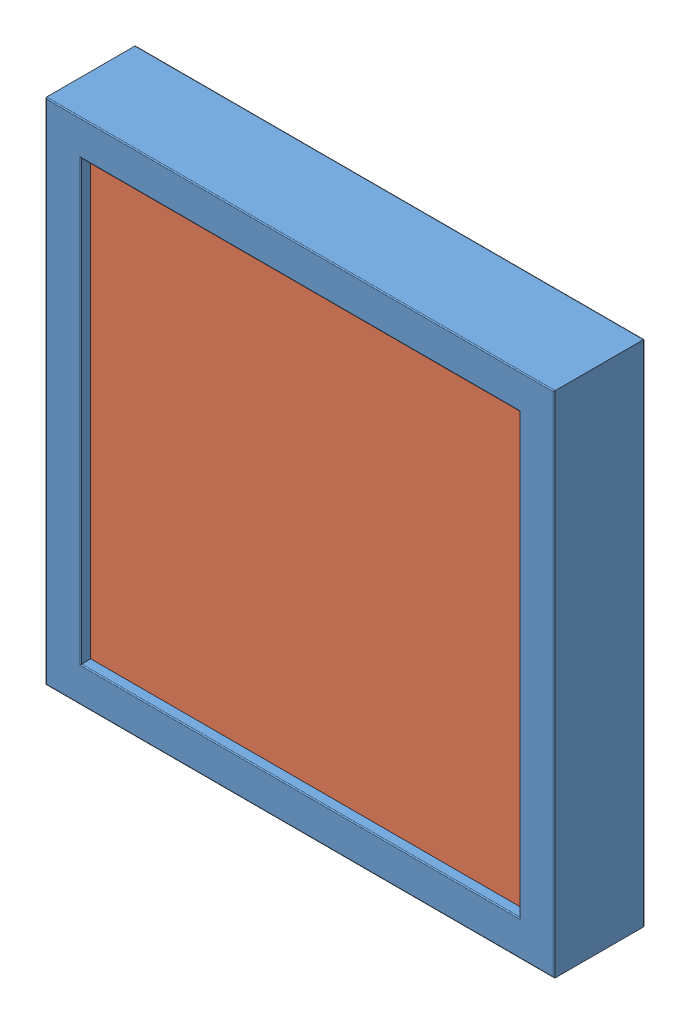
SolidWorks assembly RIBBA, configuration Default. Lengths in mm.
Overall size (254 254 45).
5 component instances, 5 part files, 16 mates.
Components (placement in the parent):
- Outer^RIBBA-1: Outer^RIBBA [Default] at origin size (254 254 45) (virtual)
- Glass^RIBBA-1: Glass^RIBBA [Default] at (0 0 -5) x (-1 0 0) z (0 0 -1) size (232 232 2) (virtual)
- Inner^RIBBA-1: Inner^RIBBA [Default] at (0 0 -7) x (-1 0 0) z (0 0 -1) size (230 230 30) (virtual)
- Matte^RIBBA-1: Matte^RIBBA [Default] at (0 0 -37) x (-1 0 0) z (0 0 -1) size (230 230 1.1) (hidden, virtual)
- Back^RIBBA-1: Back^RIBBA [Default] at (0 0 -38.1) x (-1 0 0) z (0 0 -1) size (230 230 2.65) (virtual)
Mates (geometry in assembly coordinates):
- InPlace1: in place: plane of Outer^RIBBA-1 through (0 0 -5) normal (0 0 -1); plane of Glass^RIBBA-1 through (0 0 -5) normal (0 0 -1); moOrthogonalPlaneRef_w of Outer^RIBBA-1 through (0 0 -5) normal (0 0 -1); unknown of Glass^RIBBA-1; plane of Outer^RIBBA-1 through (0 0 -5) normal (0 0 -1); plane of Glass^RIBBA-1 through (0 0 -5) normal (-1 0 0); plane of Outer^RIBBA-1 through (0 0 -5) normal (0 0 -1); unknown of Glass^RIBBA-1
- Coincident1: coincident aligned: plane of Outer^RIBBA-1; plane of Glass^RIBBA-1
- Coincident2: coincident aligned: moOrthogonalPlaneRef_w of Outer^RIBBA-1 through (0 0 -5) normal (0 1 0); plane of Glass^RIBBA-1 through (0 0 -5) normal (0 1 0)
- Coincident3: coincident anti-aligned: moOrthogonalPlaneRef_w of Outer^RIBBA-1 through (0 0 -5) normal (1 0 0); plane of Glass^RIBBA-1 through (0 0 -5) normal (-1 0 0)
- InPlace2: in place: plane of Glass^RIBBA-1 through (0 0 -7) normal (0 0 -1); plane of Inner^RIBBA-1 through (0 0 -7) normal (0 0 -1); plane of Glass^RIBBA-1 through (0 0 -7) normal (0 0 -1); unknown of Inner^RIBBA-1; plane of Glass^RIBBA-1 through (0 0 -7) normal (0 0 -1); plane of Inner^RIBBA-1 through (0 0 -7) normal (-1 0 0); plane of Glass^RIBBA-1 through (0 0 -7) normal (0 0 -1); unknown of Inner^RIBBA-1
- Coincident4: coincident aligned: plane of Glass^RIBBA-1; plane of Inner^RIBBA-1
- Coincident5: coincident aligned: moOrthogonalPlaneRef_w of Glass^RIBBA-1 through (0 0 -7) normal (0 1 0); plane of Inner^RIBBA-1 through (0 0 -7) normal (0 1 0)
- Coincident6: coincident anti-aligned: moOrthogonalPlaneRef_w of Glass^RIBBA-1 through (0 0 -7) normal (1 0 0); plane of Inner^RIBBA-1 through (0 0 -7) normal (-1 0 0)
- InPlace3: in place: plane of Inner^RIBBA-1 through (0 0 -37) normal (0 0 -1); plane of Matte^RIBBA-1 through (0 0 -37) normal (0 0 -1); plane of Inner^RIBBA-1 through (0 0 -37) normal (0 0 -1); unknown of Matte^RIBBA-1; plane of Inner^RIBBA-1 through (0 0 -37) normal (0 0 -1); plane of Matte^RIBBA-1 through (0 0 -37) normal (-1 0 0); plane of Inner^RIBBA-1 through (0 0 -37) normal (0 0 -1); unknown of Matte^RIBBA-1
- Coincident7: coincident aligned: plane of Inner^RIBBA-1; plane of Matte^RIBBA-1
- Coincident8: coincident aligned: moOrthogonalPlaneRef_w of Inner^RIBBA-1 through (0 0 -37) normal (0 1 0); plane of Matte^RIBBA-1 through (0 0 -37) normal (0 1 0)
- Coincident9: coincident anti-aligned: moOrthogonalPlaneRef_w of Inner^RIBBA-1 through (0 0 -37) normal (1 0 0); plane of Matte^RIBBA-1 through (0 0 -37) normal (-1 0 0)
- InPlace4: in place: plane of Matte^RIBBA-1 through (0 0 -38.1) normal (0 0 -1); plane of Back^RIBBA-1 through (0 0 -38.1) normal (0 0 -1); plane of Matte^RIBBA-1 through (0 0 -38.1) normal (0 0 -1); unknown of Back^RIBBA-1; plane of Matte^RIBBA-1 through (0 0 -38.1) normal (0 0 -1); plane of Back^RIBBA-1 through (0 0 -38.1) normal (-1 0 0); plane of Matte^RIBBA-1 through (0 0 -38.1) normal (0 0 -1); unknown of Back^RIBBA-1
- Coincident10: coincident aligned: plane of Matte^RIBBA-1; plane of Back^RIBBA-1
- Coincident11: coincident aligned: moOrthogonalPlaneRef_w of Matte^RIBBA-1 through (0 0 -38.1) normal (0 1 0); plane of Back^RIBBA-1 through (0 0 -38.1) normal (0 1 0)
- Coincident12: coincident anti-aligned: moOrthogonalPlaneRef_w of Matte^RIBBA-1 through (0 0 -38.1) normal (1 0 0); plane of Back^RIBBA-1 through (0 0 -38.1) normal (-1 0 0)
